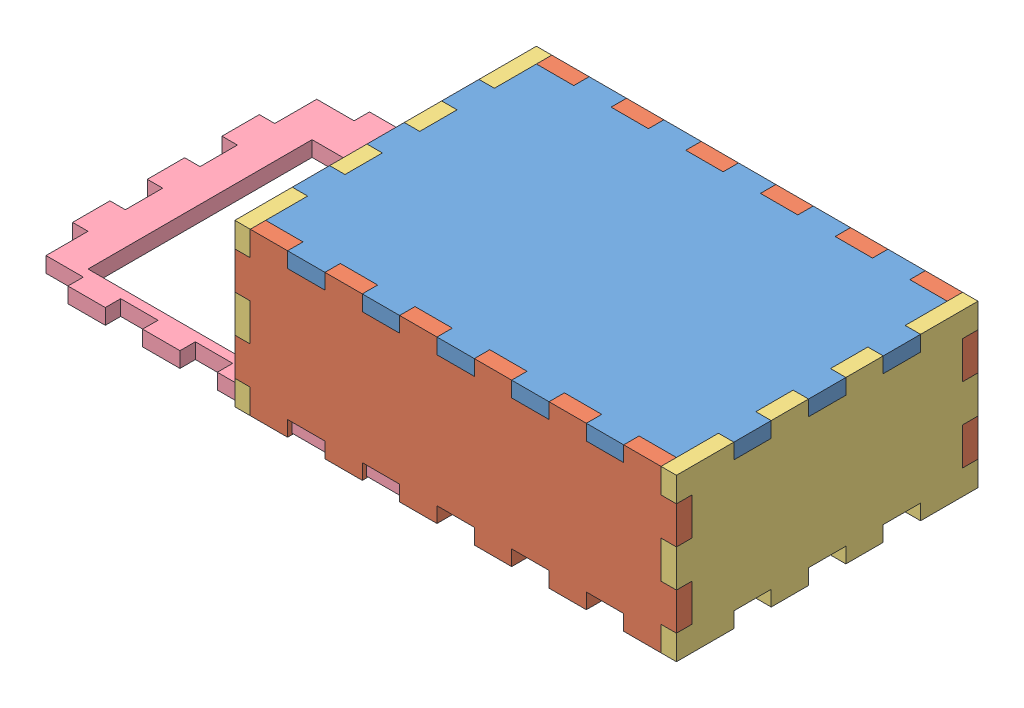
SolidWorks assembly assembly, configuration Défaut. Lengths in mm.
Overall size (142.31 34.6 65.26).
6 component instances, 4 part files, 12 mates.
Components (placement in the parent):
- bottom-1: bottom [Défaut] at (-28.8958 -0.9203 94.6) size (94.6 3.3 64.6)
- side-1: side [Défaut] at (-28.8958 -14.9203 65.6) x (-1 0 0) z (0 0 -1) size (94.6 34.6 3.3)
- side-2: side [Défaut] at (-28.8958 -14.9203 123.6) size (94.6 34.6 3.3)
- top-1: top [Défaut] at (-72.8958 -14.9203 94.6) x (0 1 0) z (0 0 1) size (34.6 3.3 64.6)
- top-2: top [Défaut] at (18.4042 -14.9203 94.6) x (0 1 0) z (0 0 1) size (34.6 3.3 64.6)
- face-1: face [Défaut] at (-76.6065 -31.6379 93.9436) size (94.6 3.3 64.6)
Mates (geometry in assembly coordinates):
- Coïncidente1: coincident anti-aligned: plane of bottom-1 through (-72.8958 2.3797 65.6) normal (0 0 -1); plane of side-1 through (-28.8958 -14.9203 65.6) normal (0 0 1)
- Coïncidente2: coincident anti-aligned: plane of bottom-1 through (-28.8958 -0.9203 94.6) normal (0 -1 0); plane of side-1 through (18.4042 -0.9203 62.3) normal (0 1 0)
- Coïncidente3: coincident anti-aligned: plane of bottom-1 through (-56.8958 2.3797 65.6) normal (1 0 0); plane of side-1 through (-56.8958 2.3797 62.3) normal (-1 0 0)
- Coïncidente6: coincident anti-aligned: plane of bottom-1 through (-28.8958 -0.9203 94.6) normal (0 -1 0); plane of side-2 through (-76.1958 -0.9203 126.9) normal (0 1 0)
- Coïncidente7: coincident anti-aligned: plane of bottom-1 through (-64.8958 2.3797 123.6) normal (-1 0 0); plane of side-2 through (-64.8958 2.3797 126.9) normal (1 0 0)
- Coïncidente8: coincident anti-aligned: plane of bottom-1 through (-72.8958 2.3797 123.6) normal (0 0 1); plane of side-2 through (-28.8958 -14.9203 123.6) normal (0 0 -1)
- Coïncidente9: coincident anti-aligned: plane of side-1 through (-72.8958 -10.9203 62.3) normal (-1 0 0); plane of top-1 through (-72.8958 -14.9203 94.6) normal (1 0 0)
- Coïncidente10: coincident anti-aligned: plane of side-1 through (-28.8958 -14.9203 65.6) normal (0 0 1); plane of top-1 through (-72.8958 -14.9203 65.6) normal (0 0 -1)
- Coïncidente11: coincident aligned: line of side-1 through (-72.8958 -2.9203 62.3) axis (0 0 1); line of top-1 through (-72.8958 -2.9203 62.3) axis (0 0 1)
- Coïncidente12: coincident anti-aligned: plane of bottom-1 through (-28.8958 -0.9203 94.6) normal (0 -1 0); plane of top-2 through (18.4042 -0.9203 74.6) normal (0 1 0)
- Coïncidente13: coincident aligned: line of side-1 through (18.4042 -18.9203 65.6) axis (-1 0 0); line of top-2 through (18.4042 -18.9203 65.6) axis (-1 0 0)
- Coïncidente14: coincident anti-aligned: plane of side-2 through (15.1042 -10.9203 126.9) normal (1 0 0); plane of top-2 through (15.1042 -14.9203 94.6) normal (-1 0 0)
